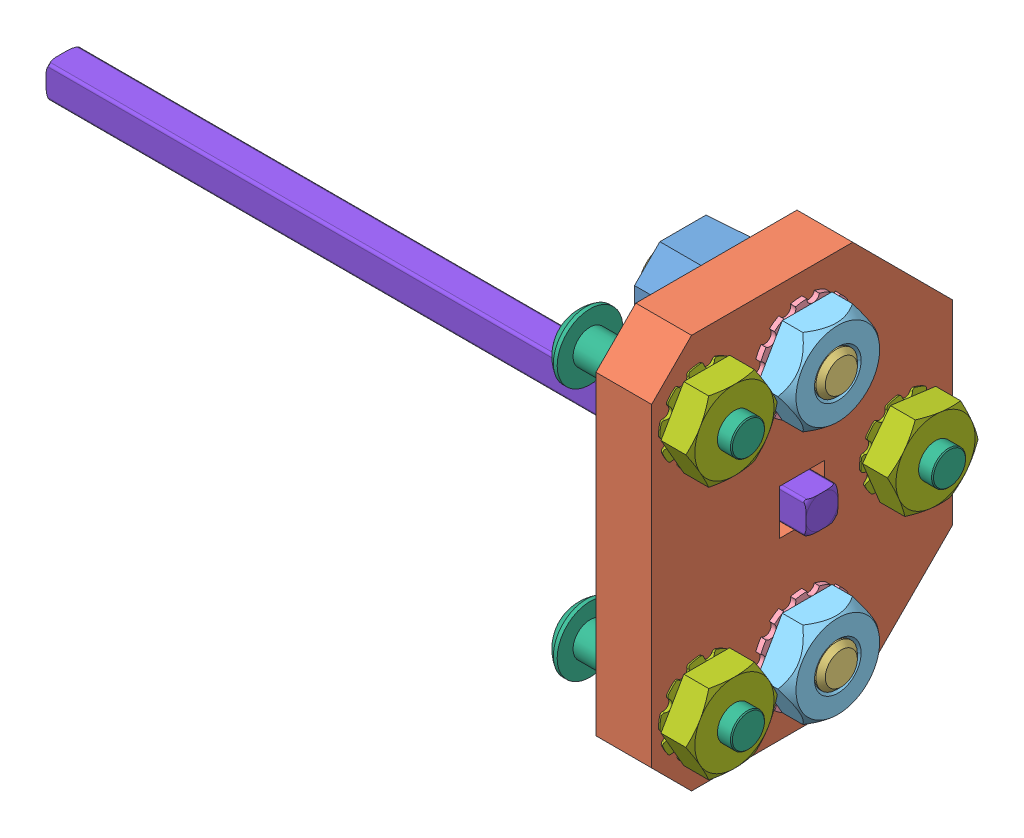
SolidWorks assembly Fab BearingMntPlt, configuration Default. Lengths in mm.
Overall size (79 39.56 30.95).
17 component instances, 8 part files, 20 mates.
Components (placement in the parent):
- BEARING-FLAT-1: BEARING-FLAT [Default] at origin size (7.04 35.56 10.16)
- 8699-18-309 Flat Bearing Mnt Plate-1: 8699-18-309 Flat Bearing Mnt Plate [Default] at (88.9762 26.416 -12.7) size (5.59 39.56 30.16)
- SCREW-832-0625-1: SCREW-832-0625 [Default] at (80.4164 39.116 -12.7) size (18.08 7.92 7.92)
- NUT-832-KEPS-1: NUT-832-KEPS [Default] at (95.0722 36.0008 -28.2806) x (0 0 -1) z (1 0 0) size (10.81 9.97 3.58)
  - 8-32 KEPS NUT-1-1: 8-32 KEPS NUT-1 [Default] at origin size (9.93 9.97 0.51)
  - 8-32 KEPS NUT-2-1: 8-32 KEPS NUT-2 [Default] at origin size (10.81 8.64 3.08)
- NUT-832-KEPS-2: NUT-832-KEPS [Default] at (95.0722 10.6008 -28.2806) x (0 0 -1) z (1 0 0) size (10.81 9.97 3.58)
  - 8-32 KEPS NUT-1-1: 8-32 KEPS NUT-1 [Default] at origin size (9.93 9.97 0.51)
  - 8-32 KEPS NUT-2-1: 8-32 KEPS NUT-2 [Default] at origin size (10.81 8.64 3.08)
- SCREW-832-0625-2: SCREW-832-0625 [Default] at (80.4164 13.716 -12.7) size (18.08 7.92 7.92)
- SCREW-632-0625-1: SCREW-632-0625 [Default] at (81.534 39.116 -2.62) size (17.73 6.59 6.59)
- tetrix_739094 Nut 6-32-1: tetrix_739094 Nut 6-32 [Default] at (96.4712 39.116 -2.62) x (0 -1 0) z (0 0 1) size (8.74 3.59 9.17)
- tetrix_739094 Nut 6-32-2: tetrix_739094 Nut 6-32 [Default] at (96.4712 13.716 -2.62) x (0 -1 0) z (0 0 1) size (8.74 3.59 9.17)
- SCREW-632-0625-2: SCREW-632-0625 [Default] at (81.534 13.716 -2.62) size (17.73 6.59 6.59)
- SCREW-632-0625-3: SCREW-632-0625 [Default] at (81.534 26.416 -22.78) x (1 0 0) z (0 -0.936997 -0.349337) size (17.73 6.59 6.59)
- tetrix_739094 Nut 6-32-3: tetrix_739094 Nut 6-32 [Default] at (96.4712 26.416 -22.78) x (0 -0.381849 0.924225) z (0 0.924225 0.381849) size (8.74 3.59 9.17)
- SHAFT-3000-1: SHAFT-3000 [Default] at (58.4642 26.416 -12.7) x (0 0 -1) z (1 0 0) size (4.18 4.18 76.41)
Mates (geometry in assembly coordinates):
- Coincident1: coincident: plane of BEARING-FLAT-1 through (88.9762 44.1997 -17.7837) normal (1 0 0); plane of 8699-18-309 Flat Bearing Mnt Plate-1 through (88.9762 26.416 -12.7) normal (1 0 0)
- Concentric1: concentric: cylinder of BEARING-FLAT-1 through (88.9762 26.416 -12.7) axis (-1 0 0) radius 2.1209; line of 8699-18-309 Flat Bearing Mnt Plate-1 through (169.8762 26.416 -12.7) axis (-1 0 0)
- Parallel1: parallel: plane of 8699-18-309 Flat Bearing Mnt Plate-1 through (88.9762 26.416 -12.7) normal (0 0 1); plane of assembly through (0 0 0) normal (0 0 1)
- Coincident3: coincident: plane of BEARING-FLAT-1 through (82.6262 32.5123 -18.6631) normal (-1 0 0); plane of SCREW-832-0625-1 through (82.6262 41.1988 -12.7) normal (1 0 0)
- Concentric2: concentric: cylinder of BEARING-FLAT-1 through (82.6262 39.116 -12.7) axis (1 0 0) radius 2.1209; cylinder of SCREW-832-0625-1 through (80.4164 39.116 -12.7) axis (-1 0 0) radius 2.0828
- Concentric3: concentric: cylinder of SCREW-832-0625-1 through (80.4164 39.116 -12.7) axis (-1 0 0) radius 2.0828; cylinder of NUT-832-KEPS-1/8-32 KEPS NUT-2-1 through (95.0722 39.116 -12.7) axis (-1 0 0) radius 2.0828
- Coincident4: coincident: plane of 8699-18-309 Flat Bearing Mnt Plate-1 through (94.5642 26.416 -12.7) normal (1 0 0); plane of NUT-832-KEPS-1/8-32 KEPS NUT-1-1 through (94.5642 45.0993 -6.7168) normal (-1 0 0)
- Parallel2: parallel: plane of ? through (95.0722 36.0008 -28.2806) normal (0 1 0); plane of assembly through (0 0 0) normal (0 1 0)
- Parallel3: parallel: plane of SCREW-832-0625-1 through (80.4164 39.116 -12.7) normal (0 1 0); plane of assembly through (0 0 0) normal (0 1 0)
- Distance4: distance = 5.588 mm: plane of SCREW-632-0625-1 through (83.3882 40.8242 -2.62) normal (1 0 0); plane of 8699-18-309 Flat Bearing Mnt Plate-1 through (88.9762 26.416 -12.7) normal (-1 0 0)
- Coincident13: coincident: plane of 8699-18-309 Flat Bearing Mnt Plate-1 through (94.5642 26.416 -12.7) normal (1 0 0); plane of tetrix_739094 Nut 6-32-1 through (94.5642 39.116 -5.8348) normal (-1 0 0)
- Parallel4: parallel: plane of tetrix_739094 Nut 6-32-1 through (96.4712 39.116 -2.62) normal (0 0 1); plane of assembly through (0 0 0) normal (0 0 1)
- Parallel5: parallel: plane of SCREW-632-0625-1 through (81.534 39.116 -2.62) normal (0 1 0); plane of assembly through (0 0 0) normal (0 1 0)
- Distance3: distance = 5.588 mm: plane of SCREW-632-0625-3 through (83.3882 25.8193 -21.1795) normal (1 0 0); plane of 8699-18-309 Flat Bearing Mnt Plate-1 through (88.9762 26.416 -12.7) normal (-1 0 0)
- Concentric6: concentric: cylinder of 8699-18-309 Flat Bearing Mnt Plate-1 through (94.5642 26.416 -22.78) axis (-1 0 0) radius 1.5875; cylinder of SCREW-632-0625-3 through (81.534 26.416 -22.78) axis (-1 0 0) radius 1.7082
- Coincident12: coincident: plane of tetrix_739094 Nut 6-32-1 through (94.5642 39.116 -5.8348) normal (-1 0 0); plane of tetrix_739094 Nut 6-32-3 through (94.5642 23.4448 -24.0076) normal (-1 0 0)
- Concentric7: concentric: cylinder of SCREW-632-0625-3 through (81.534 26.416 -22.78) axis (-1 0 0) radius 1.7082; line of tetrix_739094 Nut 6-32-3 through (146.4712 26.416 -22.78) axis (-1 0 0)
- Concentric8: concentric: cylinder of BEARING-FLAT-1 through (88.9762 26.416 -12.7) axis (-1 0 0) radius 2.1209; line of SHAFT-3000-1 through (-22.4358 26.416 -12.7) axis (1 0 0)
- Distance2: distance = 2 mm: plane of SHAFT-3000-1 through (96.5642 28.0035 -11.1125) normal (1 0 0); plane of 8699-18-309 Flat Bearing Mnt Plate-1 through (94.5642 26.416 -12.7) normal (1 0 0)
- Concentric9: concentric: cylinder of 8699-18-309 Flat Bearing Mnt Plate-1 through (94.5642 39.116 -2.62) axis (-1 0 0) radius 1.5875; cylinder of SCREW-632-0625-1 through (81.534 39.116 -2.62) axis (-1 0 0) radius 1.7082
